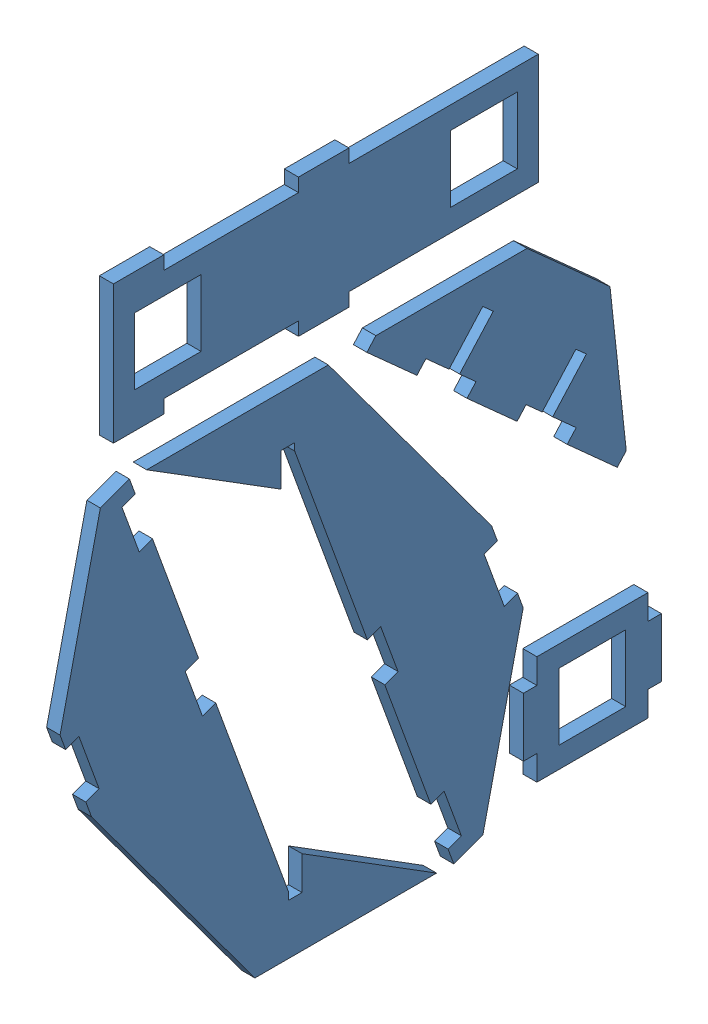
SolidWorks assembly Assem1, configuration Default. Lengths in mm.
Overall size (108.41 253.83 239.16).
6 component instances, 2 part files, 9 mates.
Components (placement in the parent):
- 12x24_Stock-1: 12x24_Stock [Default] at origin size (2.54 304.8 609.6) (hidden)
- KeelBoxJig-1: KeelBoxJig [Top] at (-138.2317 273.6145 107.9861) x (0 0 -1) z (0.939693 0.34202 0) size (52.07 40.37 19.04)
- KeelBoxJig-2: KeelBoxJig [Side] at (20.955 -474.8457 136.5425) x (1 0 0) z (0 0 -1) size (5.08 186.8 142.12)
- KeelBoxJig-3: KeelBoxJig [Side] at (20.955 368.6624 291.2673) size (5.08 186.8 142.12)
- KeelBoxJig-4: KeelBoxJig [Bottom] at (-94.7952 88.7947 -128.0459) x (0 -1 0) z (0.939693 0 -0.34202) size (52.07 152.52 59.86)
- KeelBoxJig-5: KeelBoxJig [MatePlate] at (83.82 386.7884 -203.4232) x (0 -0.667975 -0.744184) z (1 0 0) size (127 43.18 5.08)
Mates (geometry in assembly coordinates):
- Coincident1: coincident aligned: plane of KeelBoxJig-2 through (7.62 -474.8457 136.5425) normal (1 0 0); plane of KeelBoxJig-3 through (7.62 368.6624 291.2673) normal (1 0 0)
- Coincident2: coincident aligned: plane of KeelBoxJig-2 through (7.62 -474.8457 136.5425) normal (1 0 0); plane of KeelBoxJig-4 through (7.62 60.2197 120.7975) normal (1 0 0)
- Coincident3: coincident aligned: plane of KeelBoxJig-1 through (7.62 -135.5909 79.4111) normal (1 0 0); plane of KeelBoxJig-2 through (7.62 -474.8457 136.5425) normal (1 0 0)
- Coincident4: coincident aligned: plane of KeelBoxJig-2 through (7.62 -474.8457 136.5425) normal (1 0 0); plane of KeelBoxJig-5 through (7.62 386.7884 -203.4232) normal (1 0 0)
- Coincident5: coincident anti-aligned: plane of 12x24_Stock-1 through (2.54 0 0) normal (1 0 0); plane of KeelBoxJig-2 through (2.54 -474.8457 136.5425) normal (-1 0 0)
- Parallel1: parallel aligned: line of 12x24_Stock-1 through (2.54 152.4 -304.8) axis (0 0 1); line of KeelBoxJig-2 through (7.62 40.1788 200.0425) axis (0 0 1)
- Parallel2: parallel aligned: line of 12x24_Stock-1 through (2.54 152.4 -304.8) axis (0 0 1); line of KeelBoxJig-4 through (7.62 102.1297 211.3095) axis (0 0 1)
- Parallel3: parallel aligned: line of 12x24_Stock-1 through (2.54 152.4 -304.8) axis (0 0 1); line of KeelBoxJig-1 through (7.62 -94.5699 79.4111) axis (0 0 1)
- Parallel4: parallel anti-aligned: line of 12x24_Stock-1 through (2.54 152.4 -304.8) axis (0 0 1); line of KeelBoxJig-5 through (7.62 40.7765 182.1122) axis (0 0 -1)
